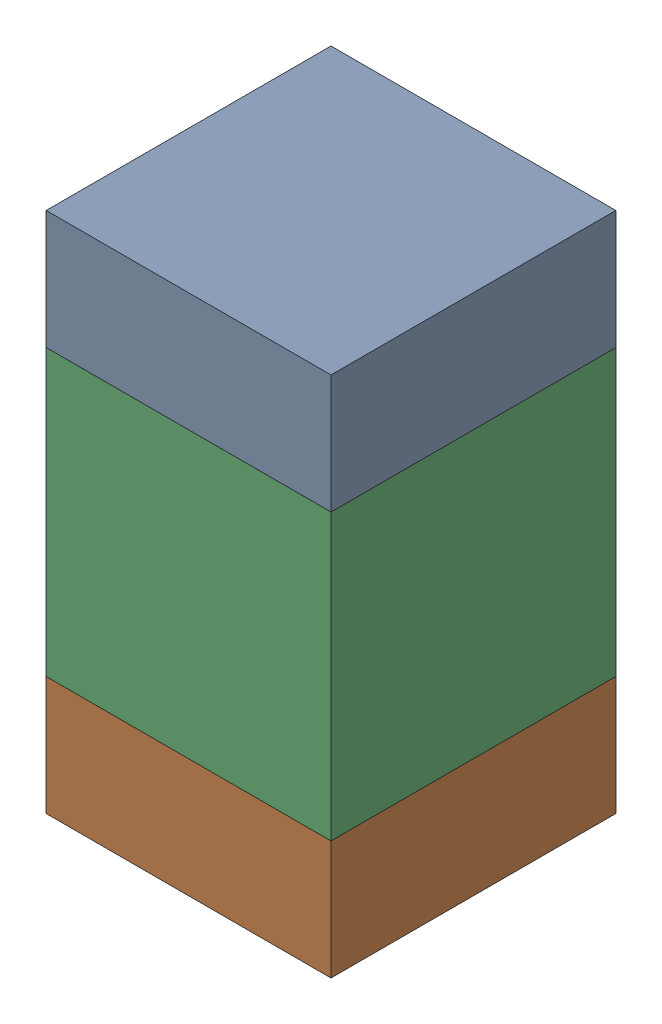
SolidWorks assembly C107_2PCB, configuration Default. Lengths in mm.
Overall size (0.6 1.1 0.6).
6 component instances, 2 part files, 0 mates.
Components (placement in the parent):
- 854785296-1: 854785296 [Default] at (99.9 87.825 0) size (0.6 0.25 0.6)
  - Extruded_10-1: Extruded_10 [Default] at origin size (0.6 0.25 0.6)
- 854785296-2: 854785296 [Default] at (99.9 86.975 0) size (0.6 0.25 0.6)
  - Extruded_10-1: Extruded_10 [Default] at origin size (0.6 0.25 0.6)
- 761606048-1: 761606048 [Default] at (99.9 87.4 0) size (0.6 0.6 0.6)
  - Extruded_9-1: Extruded_9 [Default] at origin size (0.6 0.6 0.6)
